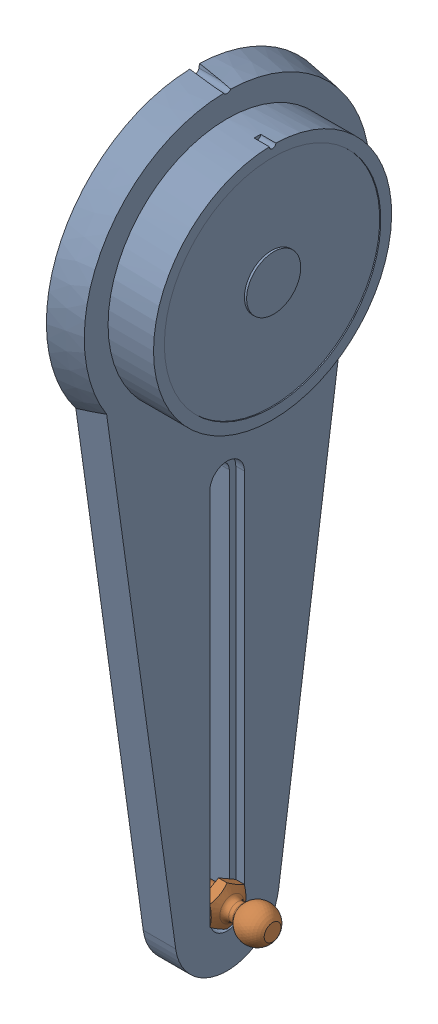
SolidWorks assembly SE_BrasCapteur, configuration Default. Lengths in mm.
Overall size (24.75 177.23 68.5).
3 component instances, 3 part files, 5 mates.
Components (placement in the parent):
- Capteur_Bras-1: Capteur_Bras [Default] at origin size (18.25 177.23 68.5)
- RotuleClipBoule-1: RotuleClipBoule [Default] at (5.5 -130 0) x (0 -0.5 0.866025) z (-1 0 0) size (9.24 8 24.5)
- Ecrou Hm M5-1: Ecrou Hm M5 [Hexagon Nut ISO - 4036 - M5 - N] at (-2.7 -130 0) x (0 0 1) z (-1 0 0) size (8 9.24 2.7)
Mates (geometry in assembly coordinates):
- Coïncidente1: coincident anti-aligned: plane of Capteur_Bras-1 through (5.5 -45 0) normal (1 0 0); plane of RotuleClipBoule-1
- Coïncidente2: coincident anti-aligned: plane of Capteur_Bras-1 through (5.5 -45 4) normal (0 0 -1); plane of RotuleClipBoule-1 through (18 -132.3094 4) normal (0 0 1)
- Coïncidente3: coincident anti-aligned: plane of Capteur_Bras-1 through (0 0 0) normal (-1 0 0); plane of Ecrou Hm M5-1 through (0 -125.3812 0) normal (1 0 0)
- Coaxial1: concentric anti-aligned: cylinder of RotuleClipBoule-1 through (-6.5 -130 0) axis (1 0 0) radius 2.5; cylinder of Ecrou Hm M5-1 through (0 -130 0) axis (-1 0 0) radius 2.1
- Distance1: distance = 130 mm: moEndPointRef_w of RotuleClipBoule-1; plane of Capteur_Bras-1
